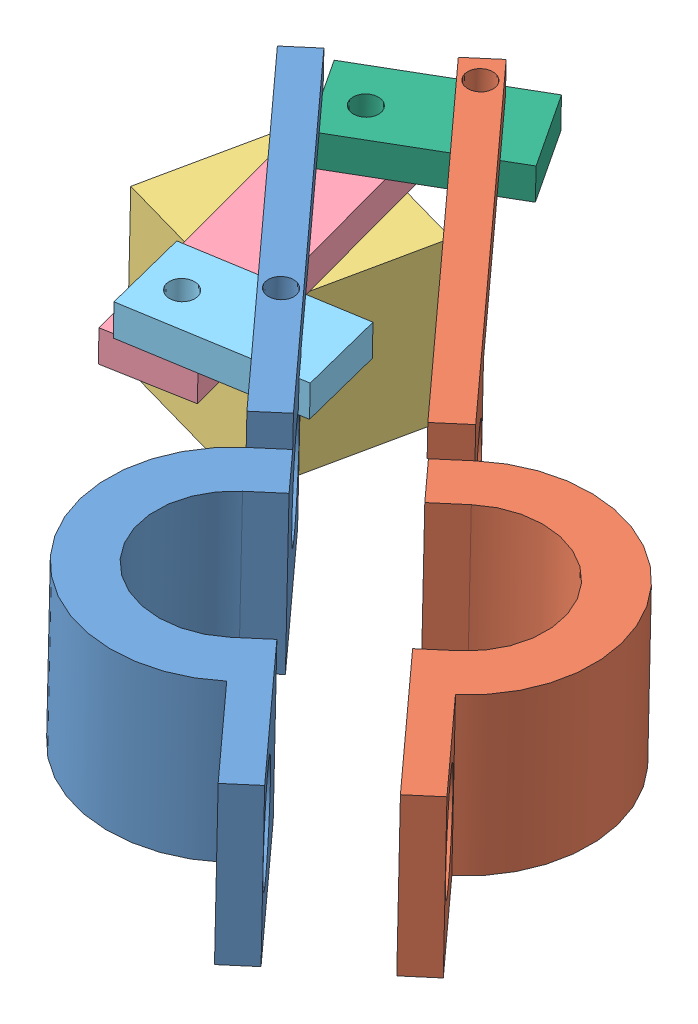
SolidWorks assembly clamp asse, configuration Default. Lengths in mm.
Overall size (52.05 17.12 53.17).
6 component instances, 6 part files, 21 mates.
Components (placement in the parent):
- clamp1-1: clamp1 [Default] at (39.7099 20.3856 29.9122) x (-0.667727 0.063142 -0.741723) z (0.742267 -0.019008 -0.669835) size (48 12 10)
- clamp2-1: clamp2 [Default] at (47.1595 20.1851 23.4741) x (0.667727 -0.063142 0.741723) z (-0.742267 0.019008 0.669835) size (48 12 10.06)
- servo-1: servo [Default] at (19.7116 18.0314 4.2152) x (0.971335 -0.062749 0.229282) z (-0.230927 -0.020266 0.97276) size (10 10 10)
- servo face-1: servo face [Default] at (19.5138 28.1611 1.3899) x (0.228542 -0.046223 0.972436) z (-0.971899 0.047028 0.230652) size (20 4 5)
- link1-2: link1 [Default] at (29.131 29.073 17.4173) x (-0.975231 0.047719 0.21598) z (-0.213879 0.045509 -0.975799) size (10 2 5)
- link2-3: link2 [Default] at (25.1444 29.8444 1.4736) x (-0.843213 0.02927 0.536783) z (-0.534614 0.059089 -0.843028) size (10 2 5)
Mates (geometry in assembly coordinates):
- Concentric1: concentric anti-aligned: cylinder of clamp1-1 through (49.4359 24.9921 37.5734) axis (-0.742267 0.019008 0.669835) radius 3; cylinder of clamp2-1 through (53.7751 24.881 33.6576) axis (0.742267 -0.019008 -0.669835) radius 3
- Parallel1: parallel anti-aligned: plane of clamp1-1 through (41.1944 20.3476 28.5726) normal (0.742267 -0.019008 -0.669835); plane of clamp2-1 through (45.675 20.2231 24.8137) normal (-0.742267 0.019008 0.669835)
- Concentric4: concentric aligned: cylinder of servo-1 through (22.4194 22.6775 10.3983) axis (0.056393 0.997824 0.034176) radius 1.5; cylinder of servo face-1 through (22.5886 25.671 10.5009) axis (0.056393 0.997824 0.034176) radius 1.5
- Concentric5: concentric anti-aligned: cylinder of clamp2-1 through (46.2892 28.9374 9.1155) axis (0.065264 0.997824 0.009425) radius 0.8; cylinder of ? through (46.2892 28.9374 9.1155) axis (-0.065264 -0.997824 -0.009425) radius 0.8
- Concentric10: concentric aligned: cylinder of servo face-1 through (51.1441 26.6138 9.2927) axis (-0.065264 -0.997824 -0.009425) radius 0.8; cylinder of ? through (51.2746 28.6094 9.3115) axis (-0.065264 -0.997824 -0.009425) radius 0.8
- Concentric11: concentric anti-aligned: cylinder of clamp1-1 through (36.931 29.4878 15.6455) axis (0.065264 0.997824 0.009425) radius 0.8; cylinder of ? through (36.931 29.4878 15.6455) axis (-0.065264 -0.997824 -0.009425) radius 0.8
- Concentric12: concentric aligned: cylinder of servo face-1 through (31.9099 27.8213 14.6396) axis (-0.065264 -0.997824 -0.009425) radius 0.8; cylinder of ? through (32.0405 29.817 14.6585) axis (-0.065264 -0.997824 -0.009425) radius 0.8
- Coincident1: coincident anti-aligned: plane of clamp2-1; plane of ? through (47.0565 28.8869 9.1457) normal (0.065264 0.997824 0.009425)
- Coincident2: coincident anti-aligned: plane of clamp1-1; plane of ? through (36.1783 29.5384 15.4936) normal (0.065264 0.997824 0.009425)
- Coincident3: coincident anti-aligned: plane of servo face-1; plane of ? through (36.0478 27.5428 15.4747) normal (-0.065264 -0.997824 -0.009425)
- Coincident5: coincident anti-aligned: plane of servo-1 through (20.2755 28.0096 4.557) normal (0.056393 0.997824 0.034176); plane of servo face-1 through (19.5138 28.1611 1.3899) normal (-0.056393 -0.997824 -0.034176)
- Concentric16: concentric anti-aligned: cylinder of clamp1-1 through (30.0143 31.3862 17.3315) axis (0.056393 0.997824 0.034176) radius 0.8; cylinder of link1-2 through (29.9943 31.032 17.3194) axis (-0.056393 -0.997824 -0.034176) radius 0.8
- Concentric17: concentric aligned: cylinder of servo face-1 through (25.0053 29.2749 18.3309) axis (-0.056393 -0.997824 -0.034176) radius 0.8; cylinder of link1-2 through (25.1181 31.2706 18.3993) axis (-0.056393 -0.997824 -0.034176) radius 0.8
- Concentric18: concentric anti-aligned: cylinder of clamp2-1 through (17.3278 33.4102 17.42) axis (0.065264 0.997824 0.009425) radius 0.8; cylinder of ? through (17.3278 33.4102 17.42) axis (-0.065264 -0.997824 -0.009425) radius 0.8
- Concentric19: concentric aligned: cylinder of servo face-1 through (20.3588 31.2443 13.5313) axis (-0.065264 -0.997824 -0.009425) radius 0.8; cylinder of ? through (20.4893 33.24 13.5501) axis (-0.065264 -0.997824 -0.009425) radius 0.8
- Coincident10: coincident anti-aligned: plane of servo face-1; plane of ? through (19.8722 31.2705 14.1269) normal (-0.065264 -0.997824 -0.009425)
- Coincident11: coincident anti-aligned: plane of clamp2-1; plane of ? through (20.0027 33.2662 14.1457) normal (0.065264 0.997824 0.009425)
- Coincident12: coincident anti-aligned: plane of servo face-1 through (19.6266 30.1568 1.4583) normal (0.056393 0.997824 0.034176); plane of link1-2 through (29.131 29.073 17.4173) normal (-0.056393 -0.997824 -0.034176)
- Concentric20: concentric aligned: cylinder of servo face-1 through (21.5772 29.9683 3.7444) axis (-0.056393 -0.997824 -0.034176) radius 0.8; cylinder of link2-3 through (21.69 31.9639 3.8128) axis (-0.056393 -0.997824 -0.034176) radius 0.8
- Concentric21: concentric anti-aligned: cylinder of clamp2-1 through (25.9261 32.1718 1.141) axis (0.056393 0.997824 0.034176) radius 0.8; cylinder of link2-3 through (25.906 31.8175 1.1288) axis (-0.056393 -0.997824 -0.034176) radius 0.8
- Coincident13: coincident anti-aligned: plane of servo face-1 through (19.6266 30.1568 1.4583) normal (0.056393 0.997824 0.034176); plane of link2-3 through (25.1444 29.8444 1.4736) normal (-0.056393 -0.997824 -0.034176)
